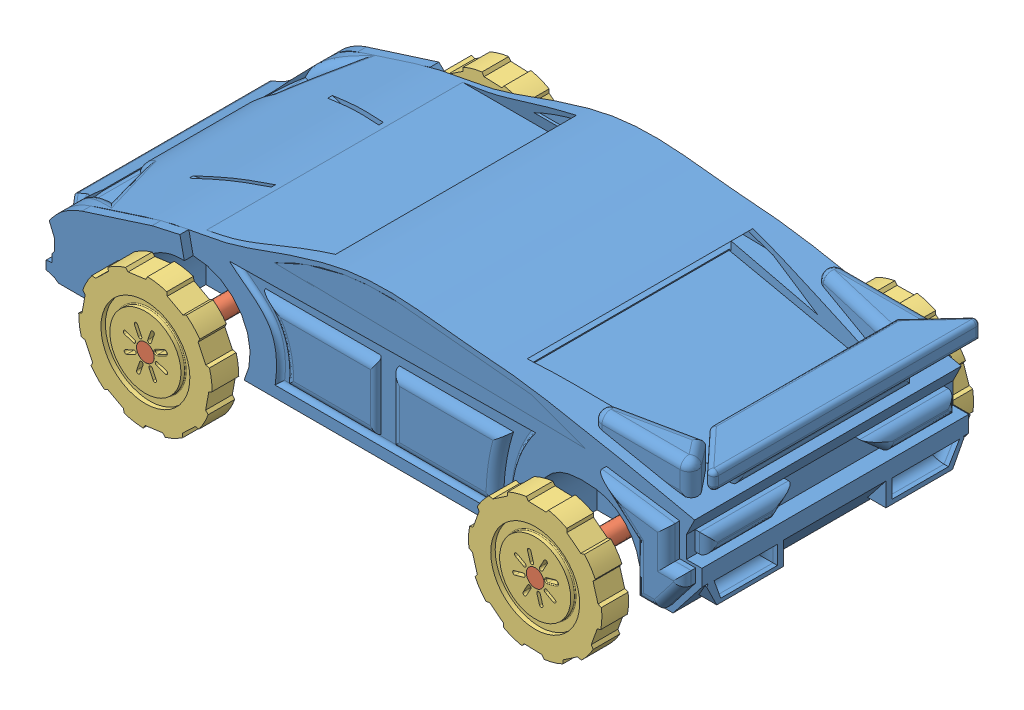
SolidWorks assembly LAMBOHORGINIASSEMBLY, configuration Default. Lengths in mm.
Overall size (455.41 703.71 106.42).
7 component instances, 3 part files, 12 mates.
Components (placement in the parent):
- LAMBHORGHINI-1: LAMBHORGHINI [Default] at (-244.886 -382.178 -39.8384) size (455.41 685.65 83.82)
- CARAXLE-1: CARAXLE [Default] at (-183.5322 -330.5612 -21.6774) x (-0.281232 0.95964 0) z (0 0 1) size (7.62 7.62 105.92)
- CarTire-1: CarTire [Default] at (-183.5322 -330.5612 -54.9514) x (0.347899 0.937532 0) z (0 0 1) size (38.1 37.56 7.74)
- CARAXLE-2: CARAXLE [Default] at (-72.0545 -330.5612 -21.5504) x (-0.281232 0.95964 0) z (0 0 1) size (7.62 7.62 105.92)
- CarTire-2: CarTire [Default] at (-72.0545 -330.5612 -54.8244) x (0.817392 -0.576081 0) z (0 0 1) size (38.1 37.56 7.74)
- CarTire-3: CarTire [Default] at (-183.5322 -330.5612 43.6006) x (0.434349 -0.900744 0) z (0 0 1) size (38.1 37.56 7.74)
- CarTire-4: CarTire [Default] at (-72.0545 -330.5612 43.7276) x (0.277079 -0.960847 0) z (0 0 1) size (38.1 37.56 7.74)
Mates (geometry in assembly coordinates):
- Coincident4: coincident anti-aligned: line of LAMBHORGHINI-1 through (-183.5322 -330.5612 -21.6774) axis (0 0 1); line of CARAXLE-1 through (-183.5322 -330.5612 18.2006) axis (0 0 -1)
- Coincident5: coincident anti-aligned: circle of LAMBHORGHINI-1; circle of CARAXLE-1
- Coincident6: coincident anti-aligned: line of CARAXLE-1 through (-183.5322 -330.5612 -54.6974) axis (0 0 1); line of CarTire-1 through (-183.5322 -330.5612 -47.3314) axis (0 0 -1)
- ProfileCenter1: profile center aligned: circle of CarTire-1; circle of CARAXLE-1
- Coincident7: coincident anti-aligned: line of LAMBHORGHINI-1 through (-72.0545 -330.5612 -21.5504) axis (0 0 1); line of CARAXLE-2 through (-72.0545 -330.5612 18.3276) axis (0 0 -1)
- Coincident8: coincident anti-aligned: circle of LAMBHORGHINI-1; circle of CARAXLE-2
- Coincident10: coincident anti-aligned: line of CARAXLE-2 through (-72.0545 -330.5612 -54.5704) axis (0 0 1); line of CarTire-2 through (-72.0545 -330.5612 -47.2044) axis (0 0 -1)
- Coincident11: coincident aligned: circle of CARAXLE-2; circle of CarTire-2
- Coincident12: coincident: line of assembly; line of assembly; axis of CARAXLE-1 through (-183.5322 -330.5612 51.2206) axis (0 0 -1); axis of CarTire-3 through (-183.5322 -330.5612 51.2206) axis (0 0 -1)
- Coincident13: coincident: circle of CARAXLE-1; circle of CarTire-3
- Coincident14: coincident aligned: line of CARAXLE-2 through (-72.0545 -330.5612 51.3476) axis (0 0 -1); line of CarTire-4 through (-72.0545 -330.5612 51.3476) axis (0 0 -1)
- Coincident15: coincident aligned: circle of CARAXLE-2; circle of CarTire-4
